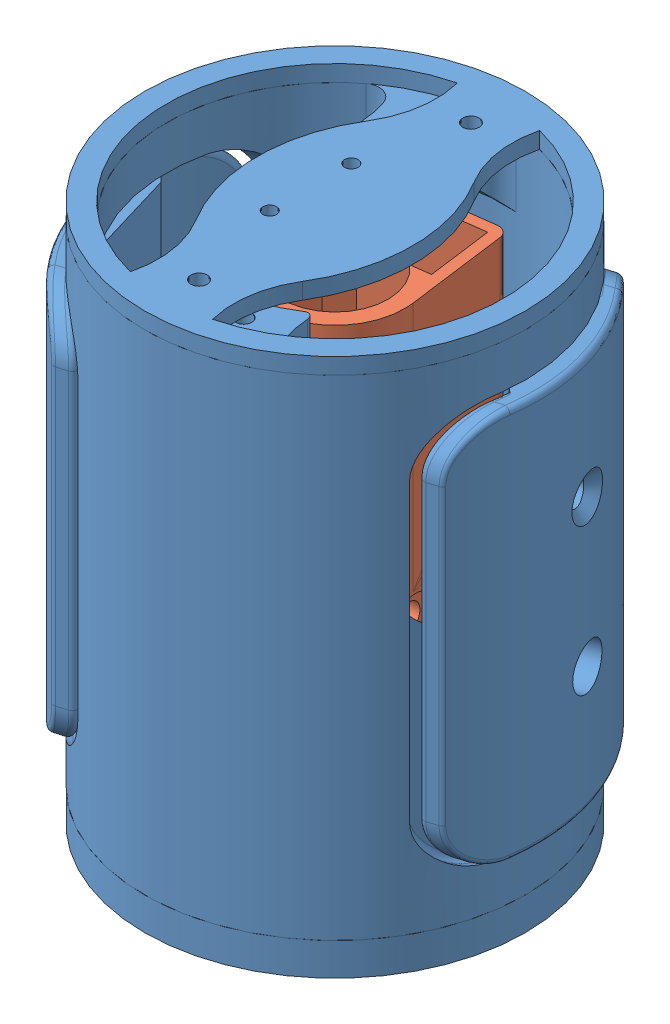
SolidWorks assembly Assem1, configuration Default. Lengths in mm.
Overall size (87.11 99 87.11).
6 component instances, 2 part files, 10 mates.
Components (placement in the parent):
- Part1-1: Part1 [accTop] at (26.7863 38.8034 53.8777) size (70 3 70)
- wiegth_holder-1: wiegth_holder [Default] at (26.7863 -33.4714 53.8777) x (0.99133 0 -0.131395) z (0.131395 0 0.99133) size (27.08 71 33.59)
- Part1-2: Part1 [top] at (26.7863 -57.1966 53.8777) x (0.286194 0 0.958172) z (-0.958172 0 0.286194) size (70 90.01 70)
- Part1-3: Part1 [side] at (26.7863 -57.1966 53.8777) x (-0.286194 0 -0.958172) z (0.958172 0 -0.286194) size (48.68 72.08 12.45)
- Part1-4: Part1 [side] at (26.7863 -57.1966 53.8777) x (0.286194 0 0.958172) z (-0.958172 0 0.286194) size (48.68 72.08 12.45)
- Part1-6: Part1 [base2] at (26.7863 -57.1966 53.8777) size (70 6 70)
Mates (geometry in assembly coordinates):
- Concentric1: concentric aligned: cylinder of Part1-2 through (26.7863 -63.1966 53.8777) axis (0 -1 0) radius 35; cylinder of Part1-6 through (26.7863 -63.1966 53.8777) axis (0 -1 0) radius 35
- Concentric2: concentric aligned: cylinder of Part1-1 through (26.7863 32.8034 53.8777) axis (0 -1 0) radius 35; cylinder of Part1-2 through (26.7863 -63.1966 53.8777) axis (0 -1 0) radius 35
- Concentric3: concentric aligned: cylinder of Part1-2 through (-6.7497 -25.6966 63.8945) axis (0.958172 0 -0.286194) radius 2.25; cylinder of Part1-4 through (-9.1459 -25.6966 64.6103) axis (0.958172 0 -0.286194) radius 4
- Concentric4: concentric anti-aligned: cylinder of Part1-2 through (26.7863 -63.1966 53.8777) axis (0 -1 0) radius 35; cylinder of Part1-4 through (26.7863 -57.1966 53.8777) axis (0 1 0) radius 37.5
- Concentric5: concentric anti-aligned: cylinder of Part1-3 through (62.7186 -25.6966 43.1452) axis (-0.958172 0 0.286194) radius 4; cylinder of Part1-4 through (-9.1459 -25.6966 64.6103) axis (0.958172 0 -0.286194) radius 4
- Concentric6: concentric anti-aligned: cylinder of Part1-2 through (26.7863 -63.1966 53.8777) axis (0 -1 0) radius 35; cylinder of Part1-3 through (26.7863 -57.1966 53.8777) axis (0 1 0) radius 37.5
- Coincident2: coincident anti-aligned: plane of Part1-1 through (-8.2137 32.8034 53.8777) normal (0 -1 0); plane of Part1-2 through (26.7863 32.8034 53.8777) normal (0 1 0)
- Coincident3: coincident anti-aligned: plane of Part1-2 through (26.7863 -57.1966 53.8777) normal (0 -1 0); plane of Part1-6 through (26.7863 -57.1966 53.8777) normal (0 1 0)
- Concentric7: concentric aligned: cylinder of wiegth_holder-1 through (26.7863 -20.9714 53.8777) axis (0 -1 0) radius 12.75; cylinder of Part1-2 through (26.7863 -63.1966 53.8777) axis (0 -1 0) radius 35
- Distance1: distance = 10.7748 mm aligned: plane of Part1-1 through (-8.2137 35.8034 53.8777) normal (0 1 0); plane of wiegth_holder-1 through (13.683 25.0286 36.8321) normal (0 1 0)
